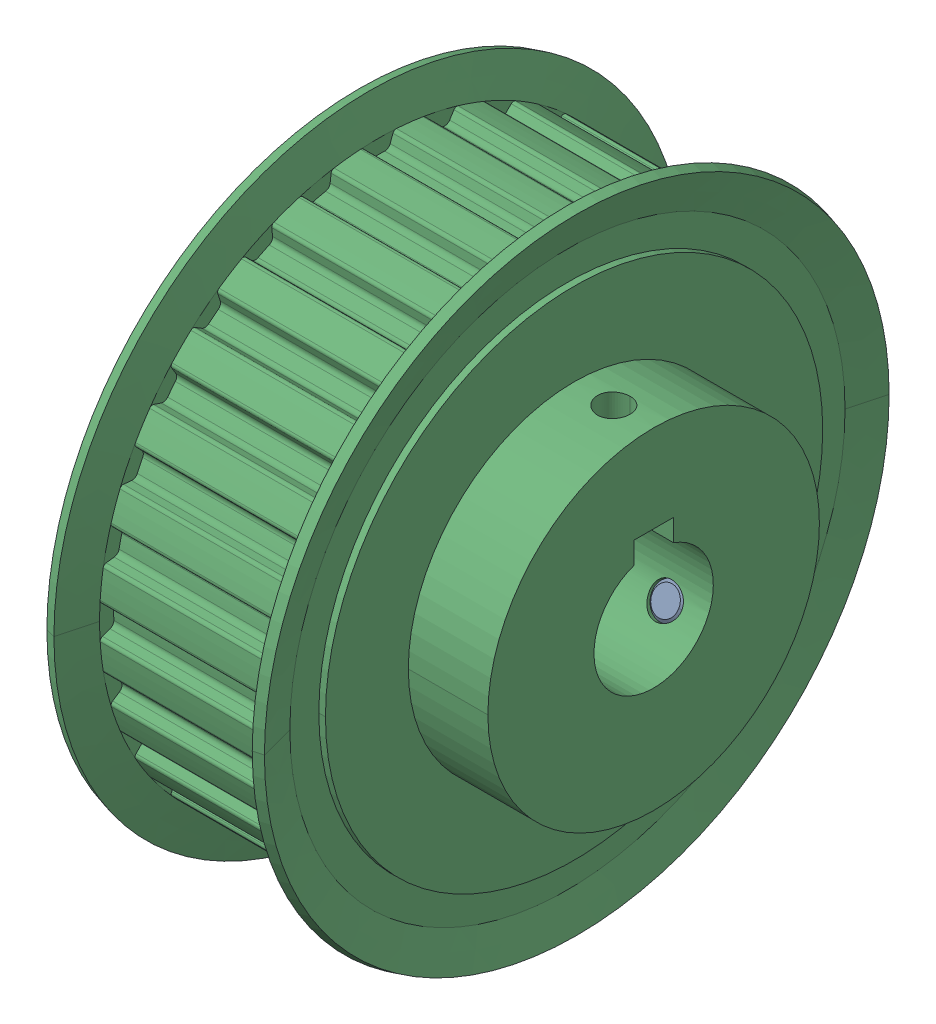
SolidWorks assembly 28tooth, configuration Default. Lengths in mm.
Overall size (44.41 95 95).
3 component instances, 2 part files, 0 mates.
Components (placement in the parent):
- ATPA28L100_B_N18_3-1: ATPA28L100_B_N18_3 [Default] at (38 -4.5 -7.7942) x (0 0.5 0.866025) z (-1 0 0) size (5 6 6)
- ATPA28L100_B_N18_3-2: ATPA28L100_B_N18_3 [Default] at (38 11.8 0) x (0 -1 0) z (-1 0 0) size (5 6 6)
- ATPA28L100_B_N18_6-1: ATPA28L100_B_N18_6 [Default] at origin size (44.41 95 95)
